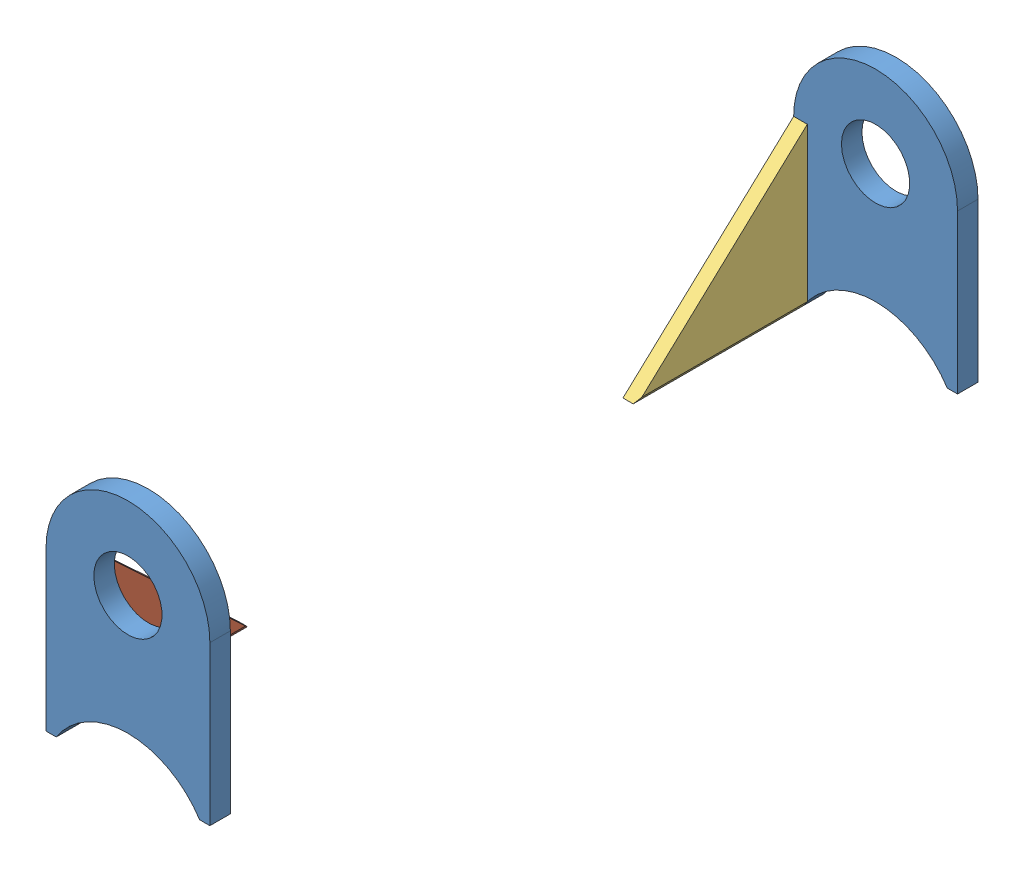
SolidWorks assembly PUTM-S-TR-GR-Motor-Attachment-Assembly-3, configuration Domyślna. Lengths in mm.
Overall size (24 35.22 112.5).
4 component instances, 3 part files, 8 mates.
Components (placement in the parent):
- PUTM-S-TR-GR-Motor-Attachment-1-1: PUTM-S-TR-GR-Motor-Attachment-1 [Domyślna] at (-55.9734 13.8613 27.1335) size (24 35.22 3)
- PUTM-S-TR-GR-Motor-Attachment-2-1: PUTM-S-TR-GR-Motor-Attachment-2 [Domyślna] at (-66.4734 -9.3564 25.6335) x (0 -1 0) z (1 0 0) size (23.22 25 2)
- PUTM-S-TR-GR-Motor-Attachment-1-2: PUTM-S-TR-GR-Motor-Attachment-1 [Domyślna] at (-55.9734 13.8613 -82.3665) size (24 35.22 3)
- PUTM-S-TR-GR-Motor-Attachment-3-1: PUTM-S-TR-GR-Motor-Attachment-3 [Domyślna] at (-67.4734 -9.3564 -80.8665) x (0 -1 0) z (-1 0 0) size (23.22 25 2)
Mates (geometry in assembly coordinates):
- Wspólnie1: coincident anti-aligned: plane of PUTM-H-DT-Motor-Attachment-1-1 through (-55.9734 13.8613 25.6335) normal (0 0 -1); plane of PUTM-H-DT-Motor-Attachment-2-1 through (-65.9734 -9.3564 25.6335) normal (0 0 1)
- Wspólnie2: coincident aligned: plane of PUTM-H-DT-Motor-Attachment-1-1 through (-67.9734 -9.3564 28.6335) normal (-1 0 0); plane of PUTM-H-DT-Motor-Attachment-2-1 through (-67.9734 -9.3564 25.6335) normal (-1 0 0)
- Wspólnie3: coincident aligned: plane of PUTM-H-DT-Motor-Attachment-1-1 through (-66.4734 -9.3564 28.6335) normal (0 -1 0); plane of PUTM-H-DT-Motor-Attachment-2-1 through (-65.9734 -9.3564 0.6335) normal (0 -1 0)
- Koncentryczne1: concentric aligned: cylinder of PUTM-H-DT-Motor-Attachment-1-1 through (-55.9734 13.8613 28.6335) axis (0 0 -1) radius 5; cylinder of PUTM-H-DT-Motor-Attachment-1-2 through (-55.9734 13.8613 -80.8665) axis (0 0 -1) radius 5
- Równolegle1: parallel aligned: plane of PUTM-H-DT-Motor-Attachment-1-1 through (-67.9734 -9.3564 28.6335) normal (-1 0 0); plane of PUTM-H-DT-Motor-Attachment-1-2 through (-67.9734 -9.3564 -80.8665) normal (-1 0 0)
- Wspólnie5: coincident aligned: plane of PUTM-H-DT-Motor-Attachment-1-2 through (-67.9734 -9.3564 -80.8665) normal (-1 0 0); plane of PUTM-H-DT-Motor-Attachment-3-1 through (-67.9734 -9.3564 -80.8665) normal (-1 0 0)
- Wspólnie6: coincident anti-aligned: plane of PUTM-H-DT-Motor-Attachment-1-2 through (-55.9734 13.8613 -80.8665) normal (0 0 1); plane of PUTM-H-DT-Motor-Attachment-3-1 through (-67.9734 -9.3564 -80.8665) normal (0 0 -1)
- Wspólnie7: coincident aligned: plane of PUTM-H-DT-Motor-Attachment-1-2 through (-66.4734 -9.3564 -80.8665) normal (0 -1 0); plane of PUTM-H-DT-Motor-Attachment-3-1 through (-67.9734 -9.3564 -55.8665) normal (0 -1 0)
